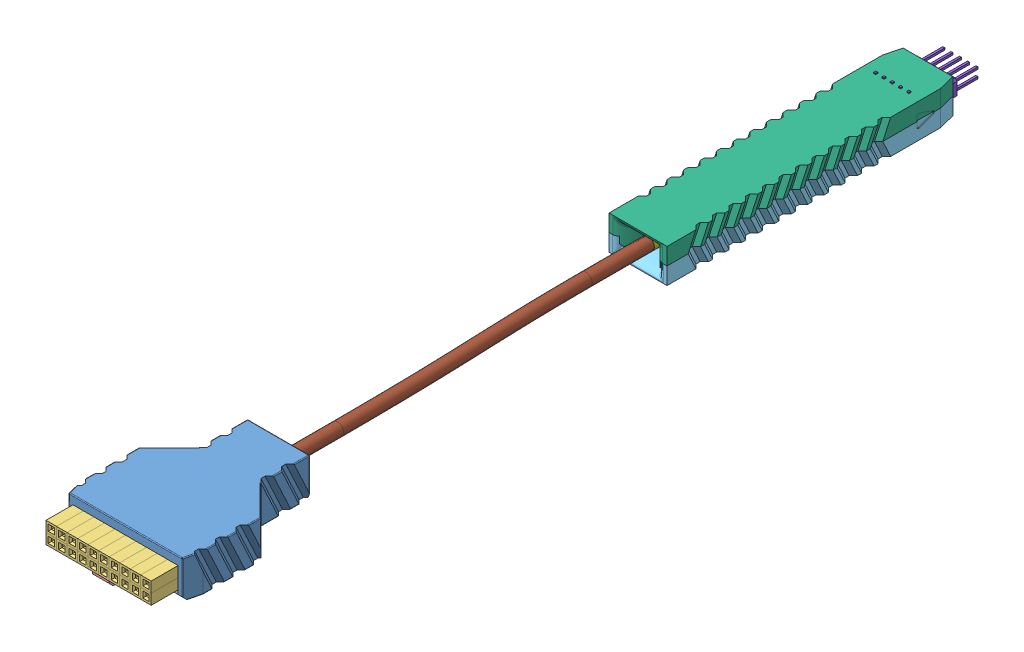
SolidWorks assembly JlinkCableForFabricationV2, configuration Default. Lengths in mm.
Overall size (29.4 9.38 208.3).
17 component instances, 13 part files, 6 mates.
Components (placement in the parent):
- ProgrammerConnector-1: ProgrammerConnector [Programmer Connector] at (0 -4.1 28.5) size (29.4 9.08 43.5)
  - ProgrammerEnclosureBody^ProgrammerConnector-1: ProgrammerEnclosureBody^ProgrammerConnector [Programmer Enclosure Body] at (0 4.1 -35) x (0 0 -1) z (-1 0 0) size (37 9.08 29.4) (virtual)
  - RoundCable^ProgrammerConnector-1: RoundCable^ProgrammerConnector [Default] at (-3.7974 -1.3 -49.3462) x (1 0 0) z (0 0 -1) size (12.39 3 25.83) (virtual)
  - PBS-2 (DS-1023 - 2x10)-1: PBS-2 (DS-1023 - 2x10) [Connector PBS-2 (DS-1023 - 2x10)] at (11.43 -1.71 -37) x (0 1 0) z (1 0 0) size (5.08 11.5 25.4)
  - ProgrammerEnclosureLid^ProgrammerConnector-1: ProgrammerEnclosureLid^ProgrammerConnector [Programmer Enclosure Lid] at (0 -2.98 -35) x (0 0 -1) z (-1 0 0) size (43 2 25.4) (virtual)
  - Copy of BH-20R^ProgrammerConnector-1: Copy of BH-20R^ProgrammerConnector [Default] at (-16.443 3.8834 -25.9394) x (1 0 0) z (0 0 -1) (suppressed, hidden, virtual)
- DeviceConnectorCable-1: DeviceConnectorCable [Device Connector] at (0 -4.1 -202.5609) x (-1 0 0) z (0 0 -1) size (14.04 8.55 78.54)
  - DeviceEnclosureLid^DeviceConnectorCable-1: DeviceEnclosureLid^DeviceConnectorCable [Device Enclosure Lid] at (0 -4.1 -37.3) x (0 0 -1) z (1 0 0) size (70.11 6.22 14.04) (virtual)
  - DeviceEnclosureBody^DeviceConnectorCable-1: DeviceEnclosureBody^DeviceConnectorCable [Device Enclosure Body] at (0 4.1 -37.3) x (0 0 -1) z (-1 0 0) size (70.5 6.52 14.04) (virtual)
  - RoundCable^DeviceConnectorCable-1: RoundCable^DeviceConnectorCable [Default] at (0.001 0 -21.5457) x (0 0 -1) z (-1 0 0) size (48.31 3 8.21) (virtual)
  - CONNFLY DS1030-02 TYPE4 2.00mm Pin Header Double Row Stack SMT Type-1: CONNFLY DS1030-02 TYPE4 2.00mm Pin Header Double Row Stack SMT Type [DS1021-2x5] at (4 0.1 -8.6597) x (1 0 0) z (0 0 -1) size (10 8.5 16.9)
  - P75-E2-1: P75-E2 [Work] at (-3.9918 -1.7697 -26.1938) x (-1 0 0) z (0 1 0) size (1.34 14.95 1.34)
    - Barrel^P75-E2-1: Barrel^P75-E2 [Default] at origin size (1.1 13 1.1) (virtual)
    - Plunger^P75-E2-1: Plunger^P75-E2 [Default] at (0 11.05 0) x (0.999365 0 -0.035623) z (0.035623 0 0.999365) size (1.29 3.9 1.29) (virtual)
- CustomCable^JlinkCableForFabricationV2-2: CustomCable^JlinkCableForFabricationV2 [Default] at origin size (3.01 4.31 90) (virtual)
  - CableSleeving^CustomCable_JlinkCableForFabricationV2-1: CableSleeving^CustomCable_JlinkCableForFabricationV2 [Cable Sleeving] at (-0.001 -4.1 -132.7016) x (0 0 1) z (-0.999996 -0.002788 0) size (90 4.3 3) (virtual)
  - Wire^CustomCable_JlinkCableForFabricationV2-1: Wire^CustomCable_JlinkCableForFabricationV2 [Wire] at origin (virtual)
Mates (geometry in assembly coordinates):
- Coincident5: coincident aligned: plane of ProgrammerConnectorCable-1/EnclosureBody^DeviceConnector-1 through (0 0 -6.5) normal (0 1 0); plane of DeviceConnector-1/DeviceEnclosureBody^DeviceConnectorCable-1 through (0 0 -165.2609) normal (0 1 0)
- Coincident6: coincident anti-aligned: plane of DeviceConnector-1 through (0 -4.1 -202.5609) normal (-1 0 0)
- Concentric3: concentric aligned: circle of ProgrammerConnector-1/RoundCable^DeviceConnectorRound-1; circle of CustomCable^JlinkCable-2/Copy of Cable^CustomCable_JlinkCable-1
- Coincident9: coincident anti-aligned: plane of ProgrammerConnector-1/RoundCable^DeviceConnectorRound-1 through (0.0026 -5.4 -42.7016) normal (0 0 -1); plane of CustomCable^JlinkCable-2/Copy of Cable^CustomCable_JlinkCable-1 through (0.0026 -5.4 -42.7016) normal (0 0 1)
- Concentric4: concentric aligned: circle of DeviceConnector-1/RoundCable^DeviceConnectorRound-1; circle of CustomCable^JlinkCable-2/Copy of Cable^CustomCable_JlinkCable-1
- Coincident10: coincident anti-aligned: plane of DeviceConnector-1/RoundCable^DeviceConnectorRound-1 through (-0.001 -4.1 -132.7016) normal (0 0 1); plane of CustomCable^JlinkCable-2/Copy of Cable^CustomCable_JlinkCable-1 through (-0.001 -4.1 -132.7016) normal (0 0 -1)
